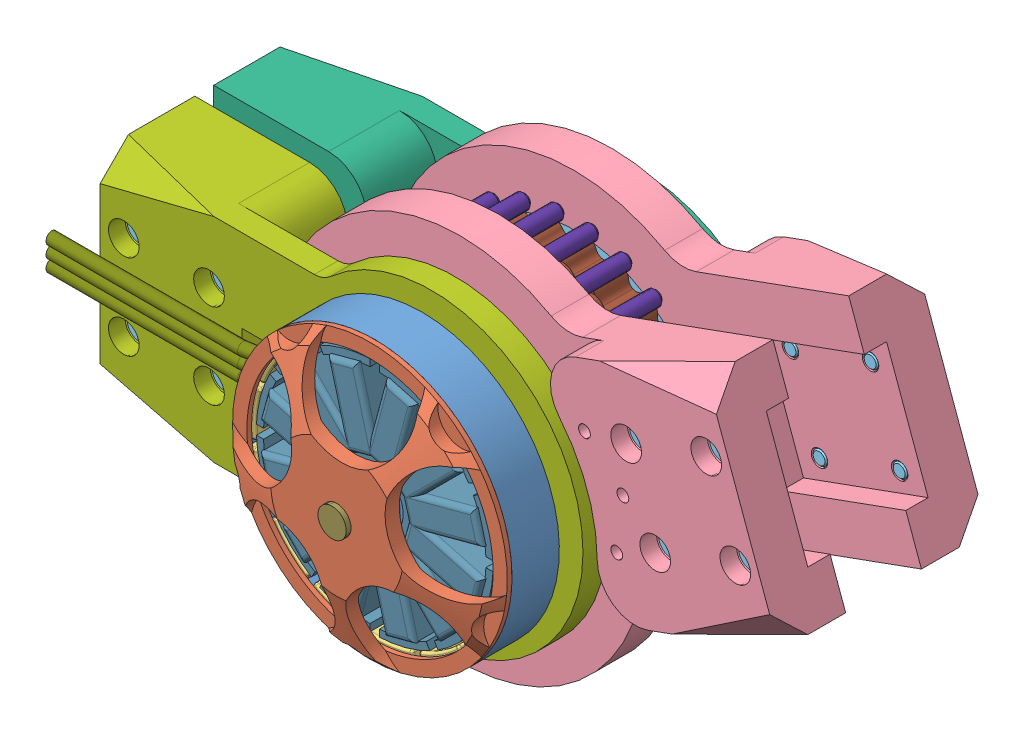
SolidWorks assembly hackaday, configuration Default. Lengths in mm.
Overall size (159.12 110.51 77).
127 component instances, 29 part files, 0 mates.
Components (placement in the parent):
- hackaday.stp-1: hackaday.stp [Default] at origin size (326.32 118.67 77)
  - 5008 motor.stp-1: 5008 motor.stp [Default] at (-7.1087 -103.7283 -19.7066) x (-0.351498 -0.936188 0) z (-0.936188 0.351498 0) size (59.12 18.06 59.12)
    - motor 5008 flux.stp-1: motor 5008 flux.stp [Default] at (33.74 9.1866 34) x (1 0 0) z (0 1 0) size (58 58 10)
    - motor 5008 top.stp-1: motor 5008 top.stp [Default] at (33.74 19.1866 34) size (59.12 8.62 59.12)
    - magnet 5008.stp-1: magnet 5008.stp [Default] at (33.74 19.1866 34) x (0.92388 0 0.382683) z (0 -1 0) size (10.37 4.02 10)
    - magnet 5008.stp-2: magnet 5008.stp [Default] at (33.74 19.1866 34) x (0.666347 0 0.745642) z (0 -1 0) size (10.37 4.02 10)
    - magnet 5008.stp-3: magnet 5008.stp [Default] at (33.74 19.1866 34) x (0.276836 0 0.960917) z (0 -1 0) size (10.37 4.02 10)
    - magnet 5008.stp-4: magnet 5008.stp [Default] at (33.74 19.1866 34) x (-0.167506 0 0.985871) z (0 -1 0) size (10.37 4.02 10)
    - magnet 5008.stp-5: magnet 5008.stp [Default] at (33.74 19.1866 34) x (-0.578671 0 0.815561) z (0 -1 0) size (10.37 4.02 10)
    - magnet 5008.stp-6: magnet 5008.stp [Default] at (33.74 19.1866 34) x (-0.875223 0 0.483719) z (0 -1 0) size (10.37 4.02 10)
    - magnet 5008.stp-7: magnet 5008.stp [Default] at (33.74 19.1866 34) x (-0.998427 0 0.05607) z (0 -1 0) size (10.37 4.02 10)
    - magnet 5008.stp-8: magnet 5008.stp [Default] at (33.74 19.1866 34) x (-0.92388 0 -0.382683) z (0 -1 0) size (10.37 4.02 10)
    - magnet 5008.stp-9: magnet 5008.stp [Default] at (33.74 19.1866 34) x (-0.666347 0 -0.745642) z (0 -1 0) size (10.37 4.02 10)
    - magnet 5008.stp-10: magnet 5008.stp [Default] at (33.74 19.1866 34) x (-0.276836 0 -0.960917) z (0 -1 0) size (10.37 4.02 10)
    - magnet 5008.stp-11: magnet 5008.stp [Default] at (33.74 19.1866 34) x (0.167506 0 -0.985871) z (0 -1 0) size (10.37 4.02 10)
    - magnet 5008.stp-12: magnet 5008.stp [Default] at (33.74 19.1866 34) x (0.578671 0 -0.815561) z (0 -1 0) size (10.37 4.02 10)
    - magnet 5008.stp-13: magnet 5008.stp [Default] at (33.74 19.1866 34) x (0.875223 0 -0.483719) z (0 -1 0) size (10.37 4.02 10)
    - magnet 5008.stp-14: magnet 5008.stp [Default] at (33.74 19.1866 34) x (0.998427 0 -0.05607) z (0 -1 0) size (10.37 4.02 10)
  - 6809_joint_out.stp-1: 6809_joint_out.stp [Default] at (-50.7987 -123.3644 -43.52) x (-0.34114 0.940012 0) z (0 0 -1) size (78 109 14)
  - 6809_joint_out.stp-2: 6809_joint_out.stp [Default] at (-50.7987 -123.3644 -25.52) x (0.34114 -0.940012 0) z (0 0 1) size (78 109 14)
  - 58x45x7_bearing.stp-1: 58x45x7_bearing.stp [Default] at (-50.7987 -123.3644 -18.52) x (1 0 0) z (0 0 -1) size (58 58 7)
  - 58x45x7_bearing.stp-2: 58x45x7_bearing.stp [Default] at (-50.7987 -123.3644 -43.52) x (1 0 0) z (0 0 -1) size (58 58 7)
  - encoder in 6809.stp-1: encoder in 6809.stp [Default] at (-50.7987 -123.3644 -42.52) x (1 0 0) z (0 0 -1) size (102 64 20)
  - motor in 6809.stp-1: motor in 6809.stp [Default] at (-50.7987 -123.3644 -26.52) size (102 64 20)
  - outer_bearing_holder.stp-1: outer_bearing_holder.stp [Default] at (-50.7987 -123.3644 -56.52) x (0 -1 0) z (0 0 -1) size (34 22 8)
  - enc_pcb.stp-1: enc_pcb.stp [Default] at (-50.7987 -123.3644 -53.52) x (1 0 0) z (0 0 -1) size (27 16 1.8)
  - enc_pcb.stp-2: enc_pcb.stp [Default] at (-50.7987 -123.3644 -58.32) x (1 0 0) z (0 0 -1) size (27 16 1.8)
  - magnet_holder.stp-1: magnet_holder.stp [Default] at (-50.7987 -123.3644 -65.52) x (0.34114 -0.940012 0) z (0 0 1) size (30 55 12)
  - bar25x25.stp-1: bar25x25.stp [Default] at (-11.3693 -108.8955 -34.52) x (0 0 -1) z (0.940012 0.34114 0) size (25.4 25.4 124) (hidden)
  - bar25x25.stp-2: bar25x25.stp [Default] at (-92.7987 -123.2644 -34.52) x (0 0 1) z (-1 0 0) size (25.4 25.4 124) (hidden)
  - inner_ring_25l.stp-1: inner_ring_25l.stp [Default] at (-50.111 -124.0904 -42.02) x (0.330465 0.943818 0) z (0 0 1) size (59.09 59.19 7)
  - inner_ring_25l.stp-2: inner_ring_25l.stp [Default] at (-51.4863 -122.6384 -27.02) x (-0.947128 0.320857 0) z (0 0 -1) size (59.09 59.19 7)
  - shaft_6mm.stp-1: shaft_6mm.stp [Default] at (-50.7987 -123.3644 -49.52) x (-0.834633 0.550807 0) z (0 0 1) size (6 6 58)
  - encoder_bearing_holder-45.stp-1: encoder_bearing_holder-45.stp [Default] at (-50.7987 -123.3644 -42.52) x (-1 0 0) z (0 0 -1) size (19 23.63 4)
  - motor 5008 stator.stp-1: motor 5008 stator.stp [Default] at (-50.7987 -123.3644 -0.52) x (1 0 0) z (0 0 -1) size (54.25 54.25 20.31)
  - sensor_cable.stp-1: sensor_cable.stp [Default] at (-130.7987 -126.7353 -57.155) x (1 0 0) z (0 1 0) size (67.53 3.96 7.65)
  - motor cable.stp-1: motor cable.stp [Default] at (-75.7987 -120.692 -13.5933) x (1 0 0) z (0 -1 0) size (54.18 4.8 7.51)
  - outer_pins.stp-1: outer_pins.stp [Default] at (-40.4962 -151.7528 -49.52) x (0.901282 0.433233 0) z (0 0 1) size (3.2 3.2 30)
  - outer_pins.stp-2: outer_pins.stp [Default] at (-47.5894 -153.3934 -49.52) x (0.978772 0.204953 0) z (0 0 1) size (3.2 3.2 30)
  - outer_pins.stp-3: outer_pins.stp [Default] at (-54.8691 -153.2888 -49.52) x (0.999379 -0.035238 0) z (0 0 1) size (3.2 3.2 30)
  - outer_pins.stp-4: outer_pins.stp [Default] at (-61.9122 -151.4452 -49.52) x (0.961906 -0.273381 0) z (0 0 1) size (3.2 3.2 30)
  - outer_pins.stp-5: outer_pins.stp [Default] at (-68.3094 -147.9696 -49.52) x (0.86853 -0.495637 0) z (0 0 1) size (3.2 3.2 30)
  - outer_pins.stp-6: outer_pins.stp [Default] at (-73.689 -143.064 -49.52) x (0.724679 -0.689087 0) z (0 0 1) size (3.2 3.2 30)
  - outer_pins.stp-7: outer_pins.stp [Default] at (-77.7382 -137.0136 -49.52) x (0.538711 -0.84249 0) z (0 0 1) size (3.2 3.2 30)
  - outer_pins.stp-8: outer_pins.stp [Default] at (-80.2219 -130.1699 -49.52) x (0.321436 -0.946931 0) z (0 0 1) size (3.2 3.2 30)
  - outer_pins.stp-9: outer_pins.stp [Default] at (-80.9955 -122.9307 -49.52) x (0.08548 -0.99634 0) z (0 0 1) size (3.2 3.2 30)
  - outer_pins.stp-10: outer_pins.stp [Default] at (-80.0143 -115.7167 -49.52) x (-0.155443 -0.987845 0) z (0 0 1) size (3.2 3.2 30)
  - outer_pins.stp-11: outer_pins.stp [Default] at (-77.3351 -108.9472 -49.52) x (-0.387333 -0.92194 0) z (0 0 1) size (3.2 3.2 30)
  - outer_pins.stp-12: outer_pins.stp [Default] at (-73.1137 -103.0155 -49.52) x (-0.596712 -0.802455 0) z (0 0 1) size (3.2 3.2 30)
  - outer_pins.stp-13: outer_pins.stp [Default] at (-67.5955 -98.2665 -49.52) x (-0.771413 -0.636335 0) z (0 0 1) size (3.2 3.2 30)
  - outer_pins.stp-14: outer_pins.stp [Default] at (-61.1011 -94.976 -49.52) x (-0.901282 -0.433233 0) z (0 0 1) size (3.2 3.2 30)
  - outer_pins.stp-15: outer_pins.stp [Default] at (-54.0079 -93.3354 -49.52) x (-0.978772 -0.204953 0) z (0 0 1) size (3.2 3.2 30)
  - outer_pins.stp-16: outer_pins.stp [Default] at (-46.7283 -93.44 -49.52) x (-0.999379 0.035238 0) z (0 0 1) size (3.2 3.2 30)
  - outer_pins.stp-17: outer_pins.stp [Default] at (-39.6852 -95.2836 -49.52) x (-0.961906 0.273381 0) z (0 0 1) size (3.2 3.2 30)
  - outer_pins.stp-18: outer_pins.stp [Default] at (-33.2879 -98.7592 -49.52) x (-0.86853 0.495637 0) z (0 0 1) size (3.2 3.2 30)
  - outer_pins.stp-19: outer_pins.stp [Default] at (-27.9084 -103.6648 -49.52) x (-0.724679 0.689087 0) z (0 0 1) size (3.2 3.2 30)
  - outer_pins.stp-20: outer_pins.stp [Default] at (-23.8591 -109.7153 -49.52) x (-0.538711 0.84249 0) z (0 0 1) size (3.2 3.2 30)
  - outer_pins.stp-21: outer_pins.stp [Default] at (-21.3754 -116.5589 -49.52) x (-0.321436 0.946931 0) z (0 0 1) size (3.2 3.2 30)
  - outer_pins.stp-22: outer_pins.stp [Default] at (-20.6018 -123.7981 -49.52) x (-0.08548 0.99634 0) z (0 0 1) size (3.2 3.2 30)
  - outer_pins.stp-23: outer_pins.stp [Default] at (-21.583 -131.0121 -49.52) x (0.155443 0.987845 0) z (0 0 1) size (3.2 3.2 30)
  - outer_pins.stp-24: outer_pins.stp [Default] at (-24.2622 -137.7816 -49.52) x (0.387333 0.92194 0) z (0 0 1) size (3.2 3.2 30)
  - outer_pins.stp-25: outer_pins.stp [Default] at (-28.4836 -143.7133 -49.52) x (0.596712 0.802455 0) z (0 0 1) size (3.2 3.2 30)
  - outer_pins.stp-26: outer_pins.stp [Default] at (-34.0018 -148.4623 -49.52) x (0.771413 0.636335 0) z (0 0 1) size (3.2 3.2 30)
  - inner_pins.stp-1: inner_pins.stp [Default] at (-70.2001 -131.4008 -20.52) x (1 0 0) z (0 0 -1) size (3 3 30)
  - inner_pins.stp-2: inner_pins.stp [Default] at (-70.2001 -115.3281 -20.52) x (0.707107 -0.707107 0) z (0 0 -1) size (3 3 30)
  - inner_pins.stp-3: inner_pins.stp [Default] at (-58.835 -103.9629 -20.52) x (0 -1 0) z (0 0 -1) size (3 3 30)
  - inner_pins.stp-4: inner_pins.stp [Default] at (-42.7623 -103.9629 -20.52) x (-0.707107 -0.707107 0) z (0 0 -1) size (3 3 30)
  - inner_pins.stp-5: inner_pins.stp [Default] at (-31.3972 -115.3281 -20.52) x (-1 0 0) z (0 0 -1) size (3 3 30)
  - inner_pins.stp-6: inner_pins.stp [Default] at (-31.3972 -131.4008 -20.52) x (-0.707107 0.707107 0) z (0 0 -1) size (3 3 30)
  - inner_pins.stp-7: inner_pins.stp [Default] at (-42.7623 -142.7659 -20.52) x (0 1 0) z (0 0 -1) size (3 3 30)
  - inner_pins.stp-8: inner_pins.stp [Default] at (-58.835 -142.7659 -20.52) x (0.707107 0.707107 0) z (0 0 -1) size (3 3 30)
  - 12x6x4 bearing.stp-1: 12x6x4 bearing.stp [Default] at (-50.7987 -123.3644 -46.52) size (12 12 4)
  - 18x12x4 bearing.stp-1: 18x12x4 bearing.stp [Default] at (-50.7987 -123.3644 -64.52) size (18 18 4)
  - 18x12x4 bearing.stp-2: 18x12x4 bearing.stp [Default] at (-50.111 -124.0904 -38.52) x (-0.944291 0.329113 0) z (0 0 -1) size (18 18 4)
  - 18x12x4 bearing.stp-3: 18x12x4 bearing.stp [Default] at (-50.111 -124.0904 -38.52) x (-0.863431 0.504468 0) z (0 0 1) size (18 18 4)
  - 18x12x4 bearing.stp-4: 18x12x4 bearing.stp [Default] at (-51.4863 -122.6384 -30.52) x (0.085182 -0.996365 0) z (0 0 1) size (18 18 4)
  - 18x12x4 bearing.stp-5: 18x12x4 bearing.stp [Default] at (-51.4863 -122.6384 -30.52) x (-0.162469 0.986714 0) z (0 0 -1) size (18 18 4)
  - 8x5x2_5 bearing.stp-1: 8x5x2_5 bearing.stp [Default] at (-44.4294 -103.8736 -41.02) x (-0.980599 0.196023 0) z (0 0 1) size (8 8 2.5)
  - 8x5x2_5 bearing.stp-2: 8x5x2_5 bearing.stp [Default] at (-31.7981 -113.8124 -41.02) x (-0.554779 0.831998 0) z (0 0 1) size (8 8 2.5)
  - 8x5x2_5 bearing.stp-3: 8x5x2_5 bearing.stp [Default] at (-29.8942 -129.772 -41.02) x (0.196023 0.980599 0) z (0 0 1) size (8 8 2.5)
  - 8x5x2_5 bearing.stp-4: 8x5x2_5 bearing.stp [Default] at (-39.833 -142.4033 -41.02) x (0.831998 0.554779 0) z (0 0 1) size (8 8 2.5)
  - 8x5x2_5 bearing.stp-5: 8x5x2_5 bearing.stp [Default] at (-55.7925 -144.3072 -41.02) x (0.980599 -0.196023 0) z (0 0 1) size (8 8 2.5)
  - 8x5x2_5 bearing.stp-6: 8x5x2_5 bearing.stp [Default] at (-68.4239 -134.3684 -41.02) x (0.554779 -0.831998 0) z (0 0 1) size (8 8 2.5)
  - 8x5x2_5 bearing.stp-7: 8x5x2_5 bearing.stp [Default] at (-70.3278 -118.4089 -41.02) x (-0.196023 -0.980599 0) z (0 0 1) size (8 8 2.5)
  - 8x5x2_5 bearing.stp-8: 8x5x2_5 bearing.stp [Default] at (-60.389 -105.7775 -41.02) x (-0.831998 -0.554779 0) z (0 0 1) size (8 8 2.5)
  - 8x5x2_5 bearing.stp-9: 8x5x2_5 bearing.stp [Default] at (-59.5854 -103.263 -31.02) x (-0.419199 0.907894 0) z (0 0 1) size (8 8 2.5)
  - 8x5x2_5 bearing.stp-10: 8x5x2_5 bearing.stp [Default] at (-70.9137 -114.6648 -31.02) x (-0.938397 0.34556 0) z (0 0 1) size (8 8 2.5)
  - 8x5x2_5 bearing.stp-11: 8x5x2_5 bearing.stp [Default] at (-70.8617 -130.7374 -31.02) x (-0.907894 -0.419199 0) z (0 0 1) size (8 8 2.5)
  - 8x5x2_5 bearing.stp-12: 8x5x2_5 bearing.stp [Default] at (-59.4599 -142.0658 -31.02) x (-0.34556 -0.938397 0) z (0 0 1) size (8 8 2.5)
  - 8x5x2_5 bearing.stp-13: 8x5x2_5 bearing.stp [Default] at (-43.3873 -142.0138 -31.02) x (0.419199 -0.907894 0) z (0 0 1) size (8 8 2.5)
  - 8x5x2_5 bearing.stp-14: 8x5x2_5 bearing.stp [Default] at (-32.059 -130.612 -31.02) x (0.938397 -0.34556 0) z (0 0 1) size (8 8 2.5)
  - 8x5x2_5 bearing.stp-15: 8x5x2_5 bearing.stp [Default] at (-32.111 -114.5394 -31.02) x (0.907894 0.419199 0) z (0 0 1) size (8 8 2.5)
  - 8x5x2_5 bearing.stp-16: 8x5x2_5 bearing.stp [Default] at (-43.5128 -103.211 -31.02) x (0.34556 0.938397 0) z (0 0 1) size (8 8 2.5)
  - offset 6id 12od.stp-1: offset 6id 12od.stp [Default] at (-50.7987 -123.3644 -42.52) x (-0.726007 -0.687687 0) z (0 0 1) size (12 14 16)
  - 12x6x4 bearing.stp-2: 12x6x4 bearing.stp [Default] at (-50.7987 -123.3644 -15.52) x (1 0 0) z (0 0 -1) size (12 12 4)
  - 12x6x4 bearing.stp-3: 12x6x4 bearing.stp [Default] at (-50.7987 -123.3644 -4.52) x (-0.950669 0.310208 0) z (0 0 1) size (12 12 4)
  - ANSI B18.3.5M - M3x6(1).stp-1: ANSI B18.3.5M - M3x6(1).stp [Default] at (-115.7987 -132.3644 -53.13) x (0 -1 0) z (0 0 -1) size (5.35 5.35 6)
  - ANSI B18.3.5M - M3x6(1).stp-2: ANSI B18.3.5M - M3x6(1).stp [Default] at (-115.7987 -114.3644 -53.13) x (0 -1 0) z (0 0 -1) size (5.35 5.35 6)
  - ANSI B18.3.5M - M3x6(1).stp-3: ANSI B18.3.5M - M3x6(1).stp [Default] at (-97.7987 -114.3644 -53.13) x (0 -1 0) z (0 0 -1) size (5.35 5.35 6)
  - ANSI B18.3.5M - M3x6(1).stp-4: ANSI B18.3.5M - M3x6(1).stp [Default] at (-97.7987 -132.3644 -53.13) x (0 -1 0) z (0 0 -1) size (5.35 5.35 6)
  - ANSI B18.3.5M - M3x6(1).stp-5: ANSI B18.3.5M - M3x6(1).stp [Default] at (-3.5478 -115.7909 -53.13) x (0.366871 -0.930272 0) z (0 0 -1) size (5.35 5.35 6)
  - ANSI B18.3.5M - M3x6(1).stp-6: ANSI B18.3.5M - M3x6(1).stp [Default] at (7.2319 -92.7302 -53.13) x (0.366871 -0.930272 0) z (0 0 -1) size (5.35 5.35 6)
  - ANSI B18.3.5M - M3x6(1).stp-7: ANSI B18.3.5M - M3x6(1).stp [Default] at (-9.6883 -98.8707 -53.13) x (0.366871 -0.930272 0) z (0 0 -1) size (5.35 5.35 6)
  - ANSI B18.3.5M - M3x6(1).stp-8: ANSI B18.3.5M - M3x6(1).stp [Default] at (13.3724 -109.6504 -53.13) x (0.366871 -0.930272 0) z (0 0 -1) size (5.35 5.35 6)
  - ANSI B18.3.5M - M3x6(1).stp-9: ANSI B18.3.5M - M3x6(1).stp [Default] at (-115.7987 -114.3644 -15.91) x (0 -1 0) z (0 0 1) size (5.35 5.35 6)
  - ANSI B18.3.5M - M3x6(1).stp-10: ANSI B18.3.5M - M3x6(1).stp [Default] at (-97.7987 -132.3644 -15.91) x (0 -1 0) z (0 0 1) size (5.35 5.35 6)
  - ANSI B18.3.5M - M3x6(1).stp-11: ANSI B18.3.5M - M3x6(1).stp [Default] at (-115.7987 -132.3644 -15.91) x (0 -1 0) z (0 0 1) size (5.35 5.35 6)
  - ANSI B18.3.5M - M3x6(1).stp-12: ANSI B18.3.5M - M3x6(1).stp [Default] at (-97.7987 -114.3644 -15.91) x (0 -1 0) z (0 0 1) size (5.35 5.35 6)
  - ANSI B18.3.5M - M3x6(1).stp-13: ANSI B18.3.5M - M3x6(1).stp [Default] at (-9.6883 -98.8707 -15.91) x (0.366871 -0.930272 0) z (0 0 1) size (5.35 5.35 6)
  - ANSI B18.3.5M - M3x6(1).stp-14: ANSI B18.3.5M - M3x6(1).stp [Default] at (13.3724 -109.6504 -15.91) x (0.366871 -0.930272 0) z (0 0 1) size (5.35 5.35 6)
  - ANSI B18.3.5M - M3x6(1).stp-15: ANSI B18.3.5M - M3x6(1).stp [Default] at (-3.5478 -115.7909 -15.91) x (0.366871 -0.930272 0) z (0 0 1) size (5.35 5.35 6)
  - ANSI B18.3.5M - M3x6(1).stp-16: ANSI B18.3.5M - M3x6(1).stp [Default] at (7.2319 -92.7302 -15.91) x (0.366871 -0.930272 0) z (0 0 1) size (5.35 5.35 6)
  - ANSI B18.3.1M - M2x0.4 x 10.stp-1: ANSI B18.3.1M - M2x0.4 x 10.stp [Default] at (-58.7987 -109.3644 -62.52) x (0 0 1) z (0 1 0) size (12 3.8 3.8)
  - ANSI B18.3.1M - M2x0.4 x 10.stp-2: ANSI B18.3.1M - M2x0.4 x 10.stp [Default] at (-42.7987 -109.3644 -62.52) x (0 0 1) z (0 1 0) size (12 3.8 3.8)
  - ANSI B18.3.1M - M2x0.4 x 10.stp-3: ANSI B18.3.1M - M2x0.4 x 10.stp [Default] at (-42.7987 -137.3644 -62.52) x (0 0 1) z (0 1 0) size (12 3.8 3.8)
  - ANSI B18.3.1M - M2x0.4 x 10.stp-4: ANSI B18.3.1M - M2x0.4 x 10.stp [Default] at (-58.7987 -137.3644 -62.52) x (0 0 1) z (0 1 0) size (12 3.8 3.8)
  - ANSI B18.3.1M - M2x0.4 x 10.stp-5: ANSI B18.3.1M - M2x0.4 x 10.stp [Default] at (-61.2987 -117.3644 -60.12) x (0 0 1) z (0 1 0) size (12 3.8 3.8)
  - ANSI B18.3.1M - M2x0.4 x 10.stp-6: ANSI B18.3.1M - M2x0.4 x 10.stp [Default] at (-40.2987 -129.3644 -60.12) x (0 0 1) z (0 1 0) size (12 3.8 3.8)
  - ANSI B18.3.1M - M2x0.4 x 10.stp-7: ANSI B18.3.1M - M2x0.4 x 10.stp [Default] at (-40.2987 -117.3644 -60.12) x (0 0 1) z (0 1 0) size (12 3.8 3.8)
  - ANSI B18.3.1M - M2x0.4 x 10.stp-8: ANSI B18.3.1M - M2x0.4 x 10.stp [Default] at (-61.2987 -129.3644 -60.12) x (0 0 1) z (0 1 0) size (12 3.8 3.8)
  - ANSI B18.6.7M - M3x0.5 x 4.stp-1: ANSI B18.6.7M - M3x0.5 x 4.stp [Default] at (-11.6668 -119.8012 -60.52) x (0 0 1) z (-0.366871 0.930272 0) size (6.38 5.6 5.6)
  - ANSI B18.6.7M - M3x0.5 x 4.stp-2: ANSI B18.6.7M - M3x0.5 x 4.stp [Default] at (-10.3781 -108.6954 -60.52) x (0 0 1) z (-0.366871 0.930272 0) size (6.38 5.6 5.6)
  - ANSI B18.6.7M - M3x0.5 x 4.stp-3: ANSI B18.6.7M - M3x0.5 x 4.stp [Default] at (-18.4896 -101.001 -60.52) x (0 0 1) z (-0.366871 0.930272 0) size (6.38 5.6 5.6)
  - 6mm diametric.stp-1: 6mm diametric.stp [Default] at (-50.7987 -123.3644 -62.02) x (0.866663 0.498894 0) z (0 0 -1) size (6 6 2)
  - motor_bearing_holder.stp-1: motor_bearing_holder.stp [Default] at (-50.7987 -123.3644 -47.52) x (1 0 0) z (0 0 -1) size (10 10 5)
  - 6mm diametric.stp-2: 6mm diametric.stp [Default] at (-50.7987 -123.3644 -51.02) x (1 0 0) z (0 0 -1) size (6 6 2)
  - silicon_steel.stp-1: silicon_steel.stp [Default] at (-55.2987 -117.3644 -56.32) x (1 0 0) z (0 0 -1) size (15 10 0.5)
